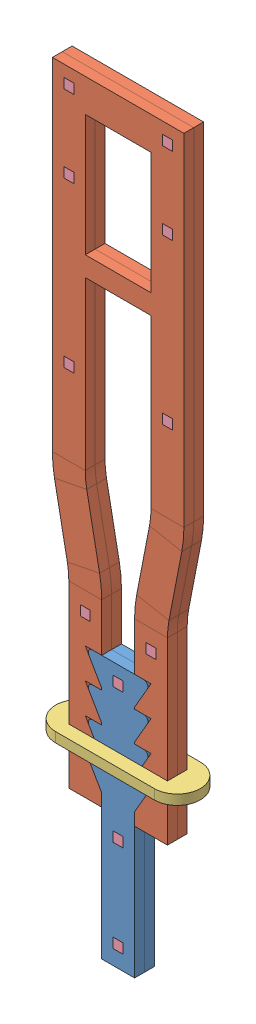
SolidWorks assembly Crutch, configuration Predeterminado. Lengths in mm.
Overall size (220 1150 70).
16 component instances, 4 part files, 44 mates.
Components (placement in the parent):
- Bottom-1: Bottom [Predeterminado] at (66.766 -281.698 407.5) size (90.7 400 15)
- Crutch-1: Crutch [Predeterminado] at (66.766 -281.698 400) size (200 950 15)
- Crutch-2: Crutch [Predeterminado] at (66.766 -281.698 415) size (200 950 15)
- Bottom-2: Bottom [Predeterminado] at (66.766 -281.698 422.5) size (90.7 400 15)
- CrutchUnion-1: CrutchUnion [Predeterminado] at (116.766 -212.1929 407.5) size (220 15 70)
- Joint-1: Joint [Predeterminado] at (191.766 533.302 407.5) x (1 0 0) z (0 -1 0) size (15 30 15)
- Joint-2: Joint [Predeterminado] at (41.766 533.302 407.5) x (1 0 0) z (0 -1 0) size (15 30 15)
- Joint-3: Joint [Predeterminado] at (166.766 -31.1027 407.5) x (1 0 0) z (0 -1 0) size (15 30 15)
- Joint-4: Joint [Predeterminado] at (191.766 283.737 407.5) x (1 0 0) z (0 -1 0) size (15 30 15)
- Joint-5: Joint [Predeterminado] at (116.766 -444.198 407.5) x (1 0 0) z (0 -1 0) size (15 30 15)
- Joint-6: Joint [Predeterminado] at (66.766 -31.1027 407.5) x (1 0 0) z (0 -1 0) size (15 30 15)
- Joint-7: Joint [Predeterminado] at (116.766 -319.198 407.5) x (-1 0 0) z (0 1 0) size (15 30 15)
- Joint-8: Joint [Predeterminado] at (116.766 -99.198 407.5) x (1 0 0) z (0 -1 0) size (15 30 15)
- Joint-9: Joint [Predeterminado] at (191.766 650.802 407.5) x (1 0 0) z (0 -1 0) size (15 30 15)
- Joint-10: Joint [Predeterminado] at (49.266 643.302 407.5) x (0 -1 0) z (-1 0 0) size (15 30 15)
- Joint-11: Joint [Predeterminado] at (41.766 283.737 407.5) x (1 0 0) z (0 -1 0) size (15 30 15)
Mates (geometry in assembly coordinates):
- Coincident2: coincident anti-aligned: plane of Crutch-1 through (66.766 -281.698 407.5) normal (0 0 1); plane of Crutch-2 through (66.766 -281.698 407.5) normal (0 0 -1)
- Coincident3: coincident aligned: plane of Crutch-1 through (191.766 668.302 400) normal (0 1 0); plane of Crutch-2 through (191.766 668.302 415) normal (0 1 0)
- Coincident4: coincident aligned: plane of Crutch-1 through (216.766 403.302 407.5) normal (1 0 0); plane of Crutch-2 through (216.766 403.302 422.5) normal (1 0 0)
- Coincident5: coincident aligned: plane of Crutch-2 through (41.766 -8.6027 422.5) normal (0 0 1); plane of Bottom-2 through (66.766 -281.698 422.5) normal (0 0 1)
- Coincident6: coincident aligned: line of Crutch-2 through (166.766 -81.698 422.5) axis (-1 0 0); line of Bottom-2 through (155.7675 -81.698 422.5) axis (-1 0 0)
- Coincident7: coincident aligned: line of Crutch-2 through (141.766 -124.9993 422.5) axis (0.5 0.866025 0); line of Bottom-2 through (141.766 -124.9993 422.5) axis (0.5 0.866025 0)
- Coincident8: coincident anti-aligned: plane of Bottom-1 through (66.766 -281.698 407.5) normal (0 0 1); plane of Bottom-2 through (66.766 -281.698 407.5) normal (0 0 -1)
- Coincident9: coincident aligned: line of Bottom-1 through (155.7675 -81.698 392.5) axis (-1 0 0); line of Crutch-1 through (91.766 -81.698 392.5) axis (-1 0 0)
- Coincident10: coincident aligned: line of Bottom-1 through (141.766 -124.9993 392.5) axis (0.5 0.866025 0); line of Crutch-1 through (141.766 -124.9993 392.5) axis (0.5 0.866025 0)
- Coincident11: coincident anti-aligned: plane of Crutch-1 through (191.766 -8.6027 392.5) normal (0 0 -1); plane of CrutchUnion-1 through (41.766 -197.1929 392.5) normal (0 0 1)
- Coincident12: coincident anti-aligned: plane of Crutch-2 through (41.766 -8.6027 422.5) normal (-1 0 0); plane of CrutchUnion-1 through (41.766 -197.1929 422.5) normal (1 0 0)
- Coincident14: coincident anti-aligned: plane of Crutch-2 through (34.266 635.802 407.5) normal (0 1 0); plane of Joint-10 through (34.266 635.802 392.5) normal (0 -1 0)
- Coincident15: coincident anti-aligned: plane of Crutch-2 through (34.266 635.802 407.5) normal (1 0 0); plane of Joint-10 through (34.266 643.302 407.5) normal (-1 0 0)
- Coincident16: coincident aligned: plane of Crutch-2 through (66.766 -281.698 422.5) normal (0 0 1); plane of Joint-10 through (34.266 650.802 422.5) normal (0 0 1)
- Coincident17: coincident anti-aligned: plane of Crutch-2 through (199.266 635.802 407.5) normal (0 1 0); plane of Joint-9 through (191.766 635.802 407.5) normal (0 -1 0)
- Coincident18: coincident aligned: plane of Crutch-2 through (66.766 -281.698 422.5) normal (0 0 1); plane of Joint-9 through (184.266 635.802 422.5) normal (0 0 1)
- Coincident19: coincident anti-aligned: plane of Crutch-2 through (199.266 635.802 407.5) normal (-1 0 0); plane of Joint-9 through (199.266 635.802 392.5) normal (1 0 0)
- Coincident20: coincident anti-aligned: plane of Crutch-2 through (34.266 518.302 407.5) normal (0 1 0); plane of Joint-2 through (41.766 518.302 407.5) normal (0 -1 0)
- Coincident21: coincident anti-aligned: plane of Crutch-2 through (34.266 518.302 407.5) normal (1 0 0); plane of Joint-2 through (34.266 518.302 392.5) normal (-1 0 0)
- Coincident22: coincident anti-aligned: plane of Crutch-2 through (199.266 518.302 407.5) normal (0 1 0); plane of Joint-1 through (191.766 518.302 407.5) normal (0 -1 0)
- Coincident24: coincident anti-aligned: plane of Crutch-2 through (184.266 518.302 407.5) normal (1 0 0); plane of Joint-1 through (184.266 518.302 392.5) normal (-1 0 0)
- Coincident25: coincident anti-aligned: plane of Crutch-2 through (34.266 268.737 407.5) normal (0 1 0); plane of Joint-11 through (41.766 268.737 407.5) normal (0 -1 0)
- Coincident26: coincident anti-aligned: plane of Crutch-2 through (34.266 268.737 407.5) normal (1 0 0); plane of Joint-11 through (34.266 268.737 392.5) normal (-1 0 0)
- Coincident27: coincident aligned: plane of Crutch-2 through (66.766 -281.698 422.5) normal (0 0 1); plane of Joint-11 through (34.266 268.737 422.5) normal (0 0 1)
- Coincident28: coincident aligned: plane of Crutch-2 through (66.766 -281.698 422.5) normal (0 0 1); plane of Joint-2 through (34.266 518.302 422.5) normal (0 0 1)
- Coincident29: coincident aligned: plane of Crutch-2 through (66.766 -281.698 422.5) normal (0 0 1); plane of Joint-1 through (184.266 518.302 422.5) normal (0 0 1)
- Coincident30: coincident anti-aligned: plane of Crutch-2 through (199.266 268.737 407.5) normal (0 1 0); plane of Joint-4 through (191.766 268.737 407.5) normal (0 -1 0)
- Coincident31: coincident anti-aligned: plane of Crutch-2 through (184.266 268.737 407.5) normal (1 0 0); plane of Joint-4 through (184.266 268.737 392.5) normal (-1 0 0)
- Coincident32: coincident aligned: plane of Crutch-2 through (66.766 -281.698 422.5) normal (0 0 1); plane of Joint-4 through (184.266 268.737 422.5) normal (0 0 1)
- Coincident33: coincident anti-aligned: plane of Crutch-2 through (59.266 -46.1027 407.5) normal (0 1 0); plane of Joint-6 through (66.766 -46.1027 407.5) normal (0 -1 0)
- Coincident34: coincident anti-aligned: plane of Crutch-2 through (59.266 -46.1027 407.5) normal (1 0 0); plane of Joint-6 through (59.266 -46.1027 392.5) normal (-1 0 0)
- Coincident35: coincident aligned: plane of Crutch-2 through (41.766 -8.6027 422.5) normal (0 0 1); plane of Joint-6 through (59.266 -46.1027 422.5) normal (0 0 1)
- Coincident36: coincident anti-aligned: plane of Crutch-2 through (174.266 -46.1027 407.5) normal (0 1 0); plane of Joint-3 through (166.766 -46.1027 407.5) normal (0 -1 0)
- Coincident37: coincident anti-aligned: plane of Crutch-2 through (159.266 -46.1027 407.5) normal (1 0 0); plane of Joint-3 through (159.266 -46.1027 392.5) normal (-1 0 0)
- Coincident38: coincident aligned: plane of Crutch-2 through (191.766 -8.6027 422.5) normal (0 0 1); plane of Joint-3 through (159.266 -46.1027 422.5) normal (0 0 1)
- Coincident40: coincident: plane of Bottom-2 through (66.766 -281.698 422.5) normal (0 0 1); plane of Joint-8 through (109.266 -114.198 422.5) normal (0 0 1)
- Coincident41: coincident: plane of Bottom-2 through (66.766 -281.698 422.5) normal (0 0 1); plane of Joint-7 through (124.266 -304.198 422.5) normal (0 0 1)
- Coincident42: coincident: plane of Bottom-2 through (66.766 -281.698 422.5) normal (0 0 1); plane of Joint-5 through (11.7596 -459.198 422.5) normal (0 0 1)
- Coincident44: coincident: plane of Bottom-2 through (109.266 -114.198 407.5) normal (0 1 0); plane of Joint-8 through (116.766 -114.198 407.5) normal (0 -1 0)
- Coincident46: coincident anti-aligned: plane of Bottom-2 through (109.266 -114.198 407.5) normal (1 0 0); plane of Joint-8 through (109.266 -114.198 392.5) normal (-1 0 0)
- Coincident47: coincident: plane of Bottom-2 through (109.266 -319.198 407.5) normal (1 0 0); plane of Joint-7 through (109.266 -304.198 392.5) normal (-1 0 0)
- Coincident48: coincident anti-aligned: plane of Bottom-2 through (109.266 -319.198 407.5) normal (0 1 0); plane of Joint-7 through (116.766 -319.198 407.5) normal (0 -1 0)
- Coincident49: coincident: plane of Bottom-2 through (109.266 -459.198 407.5) normal (0 1 0); plane of Joint-5 through (116.766 -459.198 407.5) normal (0 -1 0)
- Coincident50: coincident anti-aligned: plane of Bottom-2 through (109.266 -459.198 407.5) normal (1 0 0); plane of Joint-5 through (109.266 -459.198 392.5) normal (-1 0 0)
